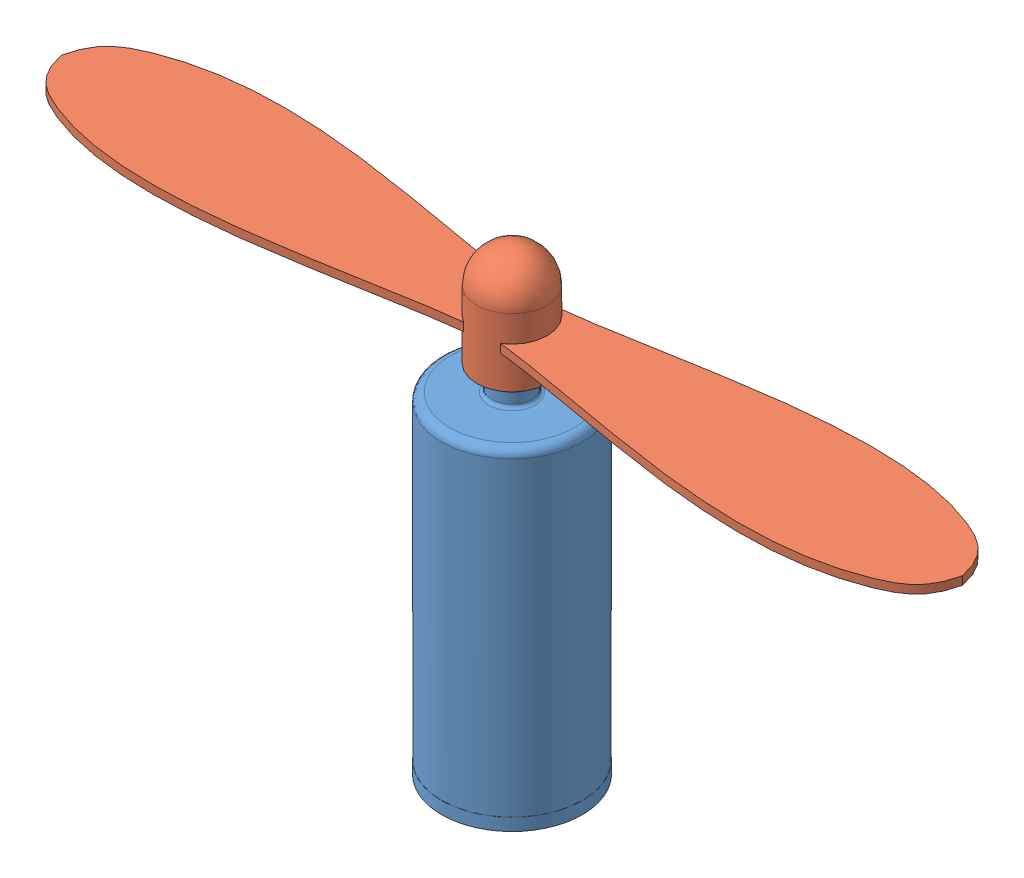
SolidWorks assembly motor-with-prop, configuration Default. Lengths in mm.
Overall size (54.45 27.97 12.44).
3 component instances, 3 part files, 4 mates.
Components (placement in the parent):
- motor-1: motor [Default] at origin size (8.5 25.55 8.5)
- prop-1: prop [Default] at (0 21.5 0) size (54.45 6.22 12.44)
- prop-volume-1: prop-volume [Default] at (0 21.5 0) size (54.45 3 54.45) (hidden)
Mates (geometry in assembly coordinates):
- Concentric1: concentric aligned: cylinder of motor-1 through (0 25.3 0) axis (0 -1 0) radius 0.5; cylinder of prop-1 through (0 26.5 0) axis (0 -1 0) radius 0.5
- Distance1: distance = 0.5 mm anti-aligned: plane of prop-1 through (0 21.5 0) normal (0 -1 0); plane of motor-1 through (0 21 0) normal (0 1 0)
- Concentric2: concentric aligned: cylinder of prop-1 through (0 27.72 0) axis (0 -1 0) radius 2.13; cylinder of prop-volume-1 through (0 24.5 0) axis (0 -1 0) radius 27.225
- Coincident2: coincident aligned: plane of prop-1 through (0 21.5 0) normal (0 -1 0); plane of prop-volume-1 through (0 21.5 0) normal (0 -1 0)
